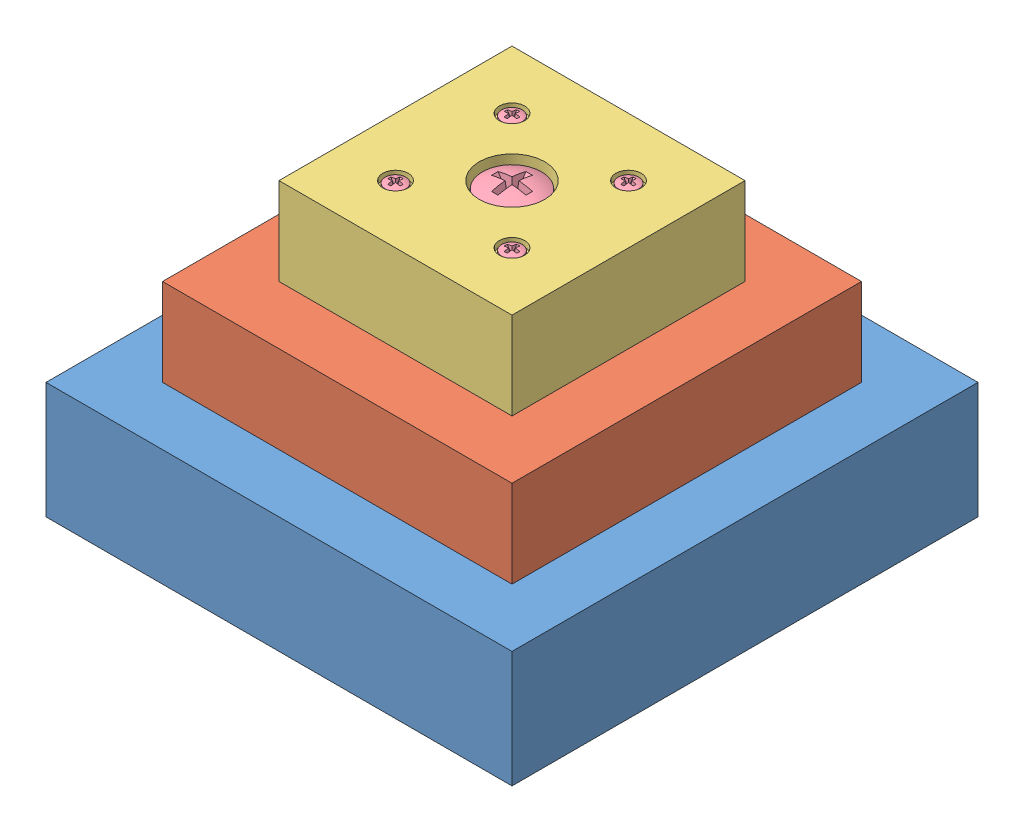
SolidWorks assembly Assem9, configuration Default. Lengths in mm.
Overall size (101.6 87 101.6).
10 component instances, 5 part files, 18 mates.
Components (placement in the parent):
- Block1-1: Block1 [Default] at origin size (101.6 25.4 101.6)
- Block2-1: Block2 [Default] at (0 25.4 0) size (76.2 19.05 76.2)
- Block3-1: Block3 [Default] at (0 44.45 0) size (50.8 19.05 50.8)
- binding head screw_ai-1: binding head screw_ai [CR-BHMS 0.25-28x2.5x1.5-N] at (0 63.5 0) x (0 -1 0) z (0 0 1) size (67.65 13.33 13.33)
- heavy hex nut_ai-1: heavy hex nut_ai [HHNUT 0.2500-28-D-N] at (0 -6.35 0) x (1 0 0) z (0 -1 0) size (12.7 14.66 6.35)
- binding head screw_ai-2: binding head screw_ai [CR-BHMS 0.086-64x0.875x0.875-N] at (12.7 63.5 -12.7) x (0 -1 0) z (0 0 1) size (23.47 4.6 4.6)
- binding head screw_ai-3: binding head screw_ai [CR-BHMS 0.086-64x0.875x0.875-N] at (-12.7 63.5 12.7) x (0 -1 0) z (0 0 1) size (23.47 4.6 4.6)
- binding head screw_ai-4: binding head screw_ai [CR-BHMS 0.086-64x0.875x0.875-N] at (12.7 63.5 12.7) x (0 -1 0) z (0 0 1) size (23.47 4.6 4.6)
- binding head screw_ai-5: binding head screw_ai [CR-BHMS 0.086-64x0.875x0.875-N] at (-12.7 63.5 -12.7) x (0 -1 0) z (0 0 1) size (23.47 4.6 4.6)
- binding head screw_ai-6: binding head screw_ai [CR-BHMS 0.086-64x0.875x0.875-N] x (0 -1 0) z (0 0 1) size (23.47 4.6 4.6)
Mates (geometry in assembly coordinates):
- Coincident1: coincident: plane of Block2-1 through (0 25.4 0) normal (0 0 1); plane of assembly through (0 0 0) normal (0 0 1)
- Coincident2: coincident: plane of Block2-1 through (0 25.4 0) normal (1 0 0); plane of assembly through (0 0 0) normal (1 0 0)
- Coincident3: coincident: plane of Block1-1 through (0 25.4 0) normal (0 1 0); plane of Block2-1 through (0 25.4 0) normal (0 -1 0)
- Coincident4: coincident: plane of Block3-1 through (0 44.45 0) normal (0 0 1); plane of assembly through (0 0 0) normal (0 0 1)
- Coincident5: coincident: plane of Block3-1 through (0 44.45 0) normal (1 0 0); plane of assembly through (0 0 0) normal (1 0 0)
- Coincident6: coincident: plane of Block2-1 through (0 44.45 0) normal (0 1 0); plane of Block3-1 through (0 44.45 0) normal (0 -1 0)
- Concentric11: concentric: cylinder of Block3-1 through (0 63.5 0) axis (0 1 0) radius 3.3782; cylinder of binding head screw_ai-1 through (0 88.9 0) axis (0 1 0) radius 3.175
- Coincident71: coincident: plane of Block3-1 through (3.3782 59.309 0) normal (0 1 0); plane of binding head screw_ai-1 through (3.175 59.309 0) normal (0 -1 0)
- Concentric2: concentric: cylinder of binding head screw_ai-1 through (0 88.9 0) axis (0 1 0) radius 3.175; cylinder of heavy hex nut_ai-1 through (0 18.6875 0) axis (0 -1 0) radius 3.175
- Coincident8: coincident: plane of Block1-1 through (0 0 0) normal (0 -1 0); plane of heavy hex nut_ai-1 through (0 0 7.3323) normal (0 1 0)
- Concentric31: concentric: cylinder of Block3-1 through (12.7 63.5 -12.7) axis (0 1 0) radius 1.2192; cylinder of binding head screw_ai-2 through (12.7 88.9 -12.7) axis (0 1 0) radius 1.0922
- Coincident91: coincident: plane of Block3-1 through (13.9192 62.23 -12.7) normal (0 1 0); plane of binding head screw_ai-2 through (13.7922 62.23 -12.7) normal (0 -1 0)
- Concentric41: concentric: cylinder of Block3-1 through (-12.7 63.5 12.7) axis (0 1 0) radius 1.2192; cylinder of binding head screw_ai-3 through (-12.7 88.9 12.7) axis (0 1 0) radius 1.0922
- Coincident101: coincident: plane of Block3-1 through (-11.4808 62.23 12.7) normal (0 1 0); plane of binding head screw_ai-3 through (-11.6078 62.23 12.7) normal (0 -1 0)
- Concentric51: concentric: cylinder of Block3-1 through (12.7 63.5 12.7) axis (0 1 0) radius 1.2192; cylinder of binding head screw_ai-4 through (12.7 88.9 12.7) axis (0 1 0) radius 1.0922
- Coincident111: coincident: plane of Block3-1 through (13.9192 62.23 12.7) normal (0 1 0); plane of binding head screw_ai-4 through (13.7922 62.23 12.7) normal (0 -1 0)
- Concentric61: concentric: cylinder of Block3-1 through (-12.7 63.5 -12.7) axis (0 1 0) radius 1.2192; cylinder of binding head screw_ai-5 through (-12.7 88.9 -12.7) axis (0 1 0) radius 1.0922
- Coincident121: coincident: plane of Block3-1 through (-11.4808 62.23 -12.7) normal (0 1 0); plane of binding head screw_ai-5 through (-11.6078 62.23 -12.7) normal (0 -1 0)
